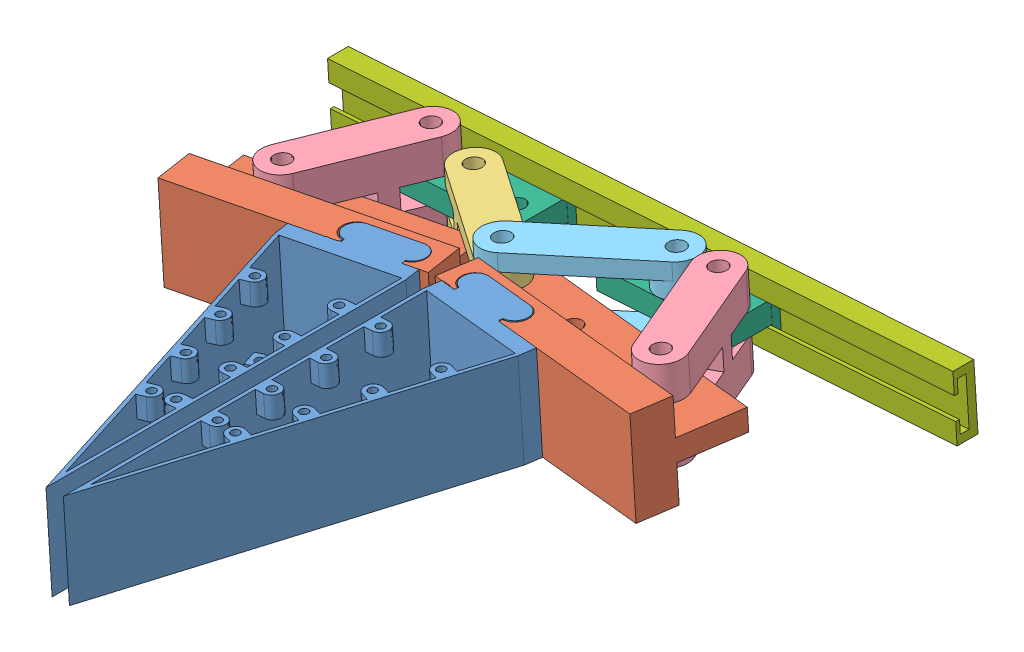
SolidWorks assembly sw-hand-closed-2, configuration Default. Lengths in mm.
Overall size (151.88 43.18 137.63).
12 component instances, 7 part files, 24 mates.
Components (placement in the parent):
- Gripper-2: Gripper [Default] at (62.809 -73.2128 41.8268) x (0.984986 0.06559 0.159689) z (0.066443 -0.99779 0) size (27.5 95.86 22)
- Platte-2: Platte [Default] at (87.1201 -63.0751 -1.5058) x (0.984986 0.06559 0.159689) z (-0.159336 -0.01061 0.987167) size (67.5 22 24)
- Platte-3: Platte [Default] at (42.4189 -61.0407 -1.5058) x (-0.984986 -0.06559 0.159689) z (0.159336 0.01061 0.987167) size (67.5 22 24)
- Gripper-3: Gripper [Default] at (66.73 -50.903 41.8268) x (-0.984986 -0.06559 0.159689) z (-0.066443 0.99779 0) size (27.5 95.86 22)
- Arm2-1: Arm2 [Default] at (69.8078 -55.2581 -15.3167) x (0.814167 0.054215 0.578094) z (-0.576816 -0.03841 0.81597) size (40 13 10)
- Arm-1: Arm [Default] at (61.4001 -72.8055 32.1886) x (-0.403942 -0.026898 0.914389) z (-0.912368 -0.060754 -0.404837) size (37 21 10)
- Arm1-1: Arm1 [Default] at (101.5056 -49.2388 45.3567) x (-0.814167 -0.054215 0.578094) z (-0.576816 -0.03841 -0.81597) size (40 8 10)
- Arm1-2: Arm1 [Default] at (59.997 -72.8489 -15.3167) x (-0.814167 -0.054215 0.578094) z (0.576816 0.03841 0.81597) size (40 8 10)
- Arm-2: Arm [Default] at (137.3755 -67.7464 2.086) x (0.403942 0.026898 0.914389) z (-0.912368 -0.060754 0.404837) size (37 21 10)
- Schiene-1: Schiene [Default] at (81.5492 -63.4461 -8.9666) x (0.99779 0.066443 0) z (0 0 1) size (30 11 14.02)
- Schiene-2: Schiene [Default] at (32.6991 -66.699 -8.9666) x (0.99779 0.066443 0) z (0 0 1) size (30 11 14.02)
- Nut-1: Nut [Default] at (149.8576 -68.393 -3.9214) x (-0.066443 0.99779 0) z (0 0 1) size (33.29 150 5)
Mates (geometry in assembly coordinates):
- Coincident8: coincident aligned: plane of Gripper-2 through (74.4705 -72.4363 41.742) normal (0.066443 -0.99779 0); plane of Platte-2 through (111.6704 -69.9592 52.865) normal (0.066443 -0.99779 0)
- Coincident10: coincident anti-aligned: plane of Gripper-2; plane of Platte-2
- Coincident11: coincident aligned: line of Gripper-2 through (61.9964 -51.2182 36.6011) axis (0.066443 -0.99779 0); line of Platte-2 through (61.9964 -51.2182 36.6011) axis (0.066443 -0.99779 0)
- Coincident12: coincident anti-aligned: circle of Platte-2; circle of Platte-3
- Coincident13: coincident aligned: plane of Platte-3 through (-2.6917 -55.5258 49.8578) normal (-0.066443 0.99779 0); plane of Gripper-3 through (35.0452 -53.0129 40.7307) normal (-0.066443 0.99779 0)
- Coincident14: coincident aligned: line of Platte-3 through (34.4481 -53.0527 37.7842) axis (0.988872 0.065849 -0.133405); line of Gripper-3 through (34.6459 -53.0395 37.7576) axis (0.988872 0.065849 -0.133405)
- Coincident15: coincident aligned: line of Platte-3 through (47.7763 -74.2139 36.1834) axis (-0.066443 0.99779 0); line of Gripper-3 through (47.7763 -74.2139 36.1834) axis (-0.066443 0.99779 0)
- Coincident16: coincident aligned: circle of Platte-2; circle of Arm2-1
- Coincident17: coincident aligned: circle of Platte-3; circle of Arm-1
- Coincident18: coincident aligned: circle of Arm2-1; circle of Arm1-1
- Coincident19: coincident anti-aligned: circle of Arm2-1; circle of Arm1-2
- Coincident20: coincident anti-aligned: circle of Platte-2; circle of Arm-2
- Concentric3: concentric aligned: circle of Arm-2; circle of Schiene-1
- Concentric4: concentric aligned: cylinder of Arm1-1 through (79.5013 -50.704 9.0226) axis (0.066443 -0.99779 0) radius 2; cylinder of Schiene-1 through (78.1827 -30.9023 9.0226) axis (0.066443 -0.99779 0) radius 2
- Concentric5: concentric anti-aligned: cylinder of Arm1-2 through (80.8833 -71.4581 9.0226) axis (-0.066443 0.99779 0) radius 2; cylinder of Schiene-1 through (78.1827 -30.9023 9.0226) axis (0.066443 -0.99779 0) radius 2
- Coincident22: coincident anti-aligned: plane of Arm-2 through (123.9264 -55.6131 -10.1323) normal (0.066443 -0.99779 0); plane of Schiene-1 through (72.2114 -59.0568 -8.9666) normal (-0.066443 0.99779 0)
- Coincident23: coincident anti-aligned: plane of Arm-1 through (52.7824 -65.3617 28.8307) normal (-0.066443 0.99779 0); plane of Schiene-2 through (30.5882 -66.8396 -8.1) normal (0.066443 -0.99779 0)
- Concentric8: concentric anti-aligned: cylinder of Arm-1 through (20.6571 -75.5186 6.6774) axis (-0.066443 0.99779 0) radius 2; cylinder of Schiene-2 through (17.9531 -34.913 6.6774) axis (0.066443 -0.99779 0) radius 2
- Concentric9: concentric aligned: cylinder of Arm2-1 through (28.3015 -58.022 11.4455) axis (0.066443 -0.99779 0) radius 2; cylinder of Schiene-2 through (26.7238 -34.3289 11.4455) axis (0.066443 -0.99779 0) radius 2
- Coincident24: coincident anti-aligned: plane of Schiene-1 through (64.8566 -56.5399 0) normal (0 0 -1); plane of assembly through (0 0 0) normal (0 0 1)
- Coincident26: coincident aligned: line of Schiene-1 through (64.8566 -56.5399 0) axis (0.99779 0.066443 0); line of Nut-1 through (-9.9776 -61.5231 0) axis (0.99779 0.066443 0)
- Coincident28: coincident aligned: line of Schiene-1 through (64.8566 -56.5399 0) axis (0.066443 -0.99779 0); line of Nut-1 through (64.192 -46.5581 0) axis (0.066443 -0.99779 0)
- Parallel2: parallel anti-aligned: plane of Gripper-2 through (66.1138 -50.944 47.3245) normal (-0.99779 -0.066443 0); plane of Gripper-3 through (63.4252 -73.1718 47.3245) normal (0.99779 0.066443 0)
- Coincident31: coincident aligned: line of Schiene-2 through (25.0122 -59.1932 0) axis (0.99779 0.066443 0); line of Nut-1 through (-0.972 -60.9235 0) axis (0.99779 0.066443 0)
